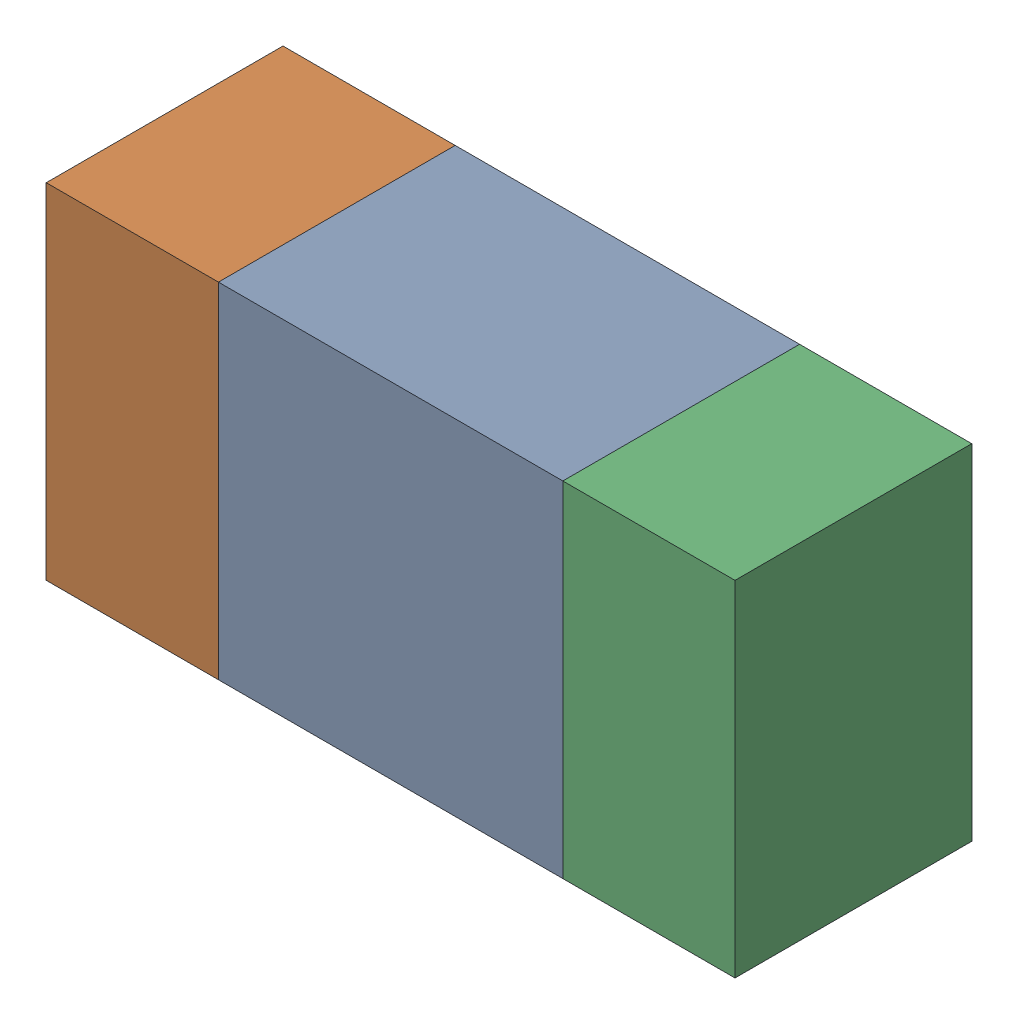
SolidWorks assembly R43, configuration ﾃﾞﾌｫﾙﾄ. Lengths in mm.
Overall size (1.6 0.8 0.55).
6 component instances, 2 part files, 0 mates.
Components (placement in the parent):
- 689261648-1: 689261648 [ﾃﾞﾌｫﾙﾄ] at (57.8 25.9999 0) size (0.8 0.8 0.55)
  - Extruded_33-1: Extruded_33 [ﾃﾞﾌｫﾙﾄ] at origin size (0.8 0.8 0.55)
- 689261512-1: 689261512 [ﾃﾞﾌｫﾙﾄ] at (57.1999 25.9999 0) size (0.4 0.8 0.55)
  - Extruded_32-1: Extruded_32 [ﾃﾞﾌｫﾙﾄ] at origin size (0.4 0.8 0.55)
- 689261512-2: 689261512 [ﾃﾞﾌｫﾙﾄ] at (58.3999 25.9999 0) size (0.4 0.8 0.55)
  - Extruded_32-1: Extruded_32 [ﾃﾞﾌｫﾙﾄ] at origin size (0.4 0.8 0.55)
